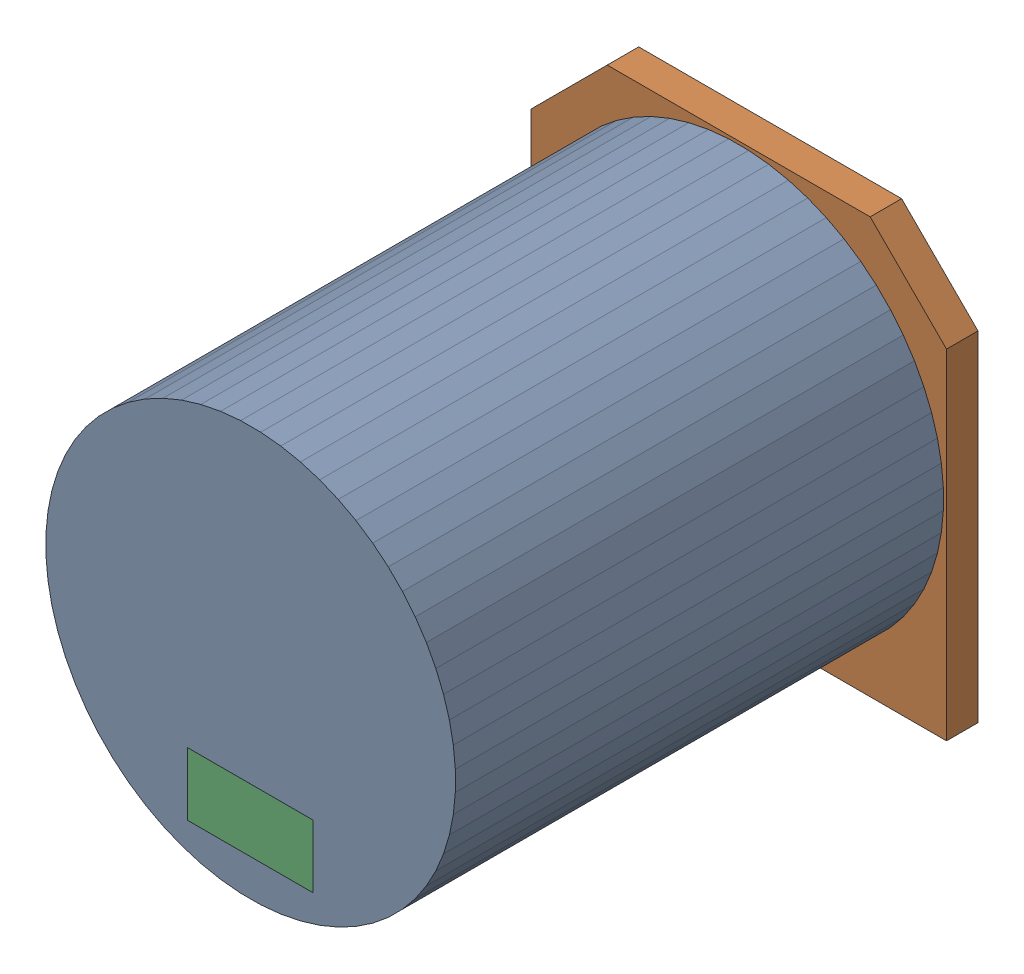
SolidWorks assembly C23, configuration Default. Lengths in mm.
Overall size (13.2 13.2 16.5).
6 component instances, 3 part files, 0 mates.
Components (placement in the parent):
- 6638397648-1: 6638397648 [Default] at (49.0343 52.8197 1) size (13 13 15.5)
  - Extruded-1: Extruded [Default] at origin size (13 13 15.5)
- 6638397568-1: 6638397568 [Default] at (49.0343 52.8197 0) size (13.2 13.2 1)
  - Extruded_2-1: Extruded_2 [Default] at origin size (13.2 13.2 1)
- 6638397808-1: 6638397808 [Default] at (49.022 48.482 16.4) size (4 2 0.1)
  - Extruded_3-1: Extruded_3 [Default] at origin size (4 2 0.1)
